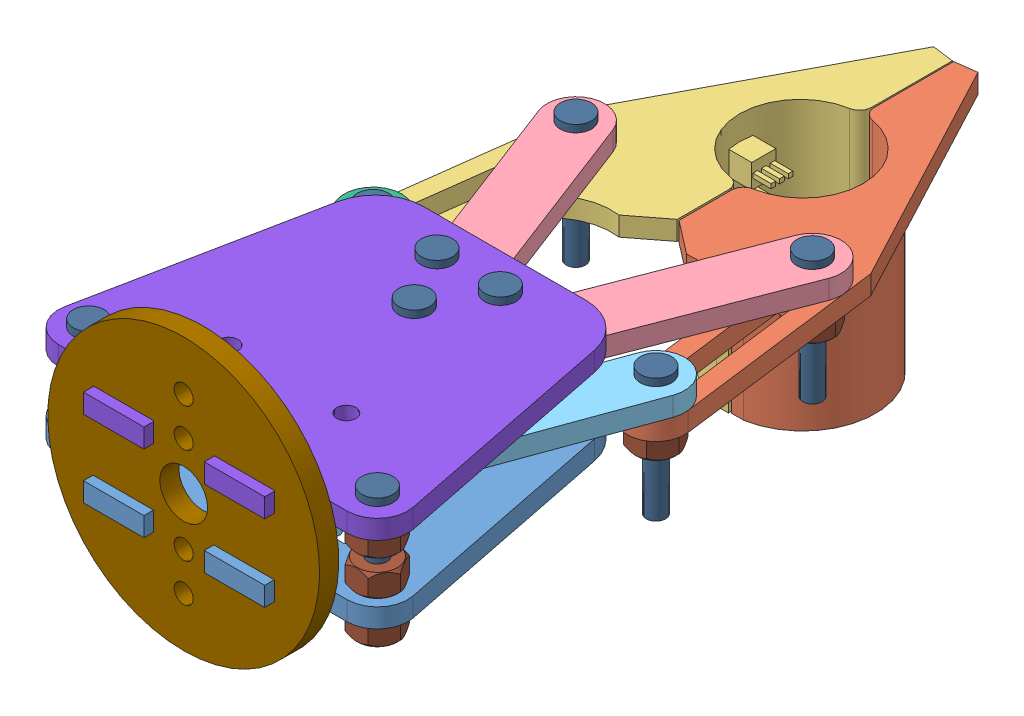
SolidWorks assembly Analyzing Arm, configuration Default. Lengths in mm.
Overall size (71.8 56.15 131.35).
40 component instances, 11 part files, 49 mates.
Components (placement in the parent):
- Gripper2-1: Gripper2 [Predeterminado] at origin size (71.8 56.15 131.35) (flexible)
  - Base grip-1: Base grip [Predeterminado] at (-28.7905 -8.0804 25) size (57.8 3.17 54.76)
  - Gripp2-3: Gripp2 [Predeterminado] at (12.4805 -1.7304 -60.3117) x (-0.991775 0 0.127995) z (0.127995 0 0.991775) size (24.38 32 79.76)
  - Gripp-3: Gripp [Predeterminado] at (-10.0632 -4.9054 -60.311) x (0.991774 0 0.127998) z (-0.127998 0 0.991774) size (24.38 32 79.76)
  - eslabon dos-1: eslabon dos [Predeterminado] at (9.1807 -1.7304 -39.3783) x (0.358372 0 -0.933579) z (0.933579 0 0.358372) size (49.52 3.17 9.53)
  - eslabon dos-2: eslabon dos [Predeterminado] at (-6.7627 -1.7304 -39.3782) x (0.358414 0 0.933563) z (-0.933563 0 0.358414) size (49.52 3.17 9.53)
  - eslabon engrane servo-1: eslabon engrane servo [Predeterminado] at (22.2724 -1.7304 -6.1668) x (-0.341868 0 0.939748) z (-0.939748 0 -0.341868) size (56.02 3.17 23.48)
  - eslabon engrane servo - copia-1: eslabon engrane servo - copia [Predeterminado] at (-10.9033 -1.7304 -9.423) x (0.341912 0 0.939732) z (-0.939732 0 0.341912) size (56.51 3.17 22.67)
  - separadores-1: separadores [Predeterminado] at (-8.5405 -4.9054 11) x (0.999665 0 -0.025874) z (0.025874 0 0.999665) size (6.35 3.17 6.35)
  - separadores-2: separadores [Predeterminado] at (-8.5405 1.4446 11) x (0.999761 0 0.021872) z (-0.021872 0 0.999761) size (6.35 3.17 6.35)
  - separadores-4: separadores [Predeterminado] at (-4.0405 -4.9054 -19) x (0.999761 0 0.021872) z (-0.021872 0 0.999761) size (6.35 3.17 6.35)
  - separadores-5: separadores [Predeterminado] at (6.4595 1.4446 -19) x (0.999761 0 0.021872) z (-0.021872 0 0.999761) size (6.35 3.17 6.35)
  - separadores-6: separadores [Predeterminado] at (-4.0405 1.4446 -19) x (0.999761 0 0.021872) z (-0.021872 0 0.999761) size (6.35 3.17 6.35)
  - separadores-7: separadores [Predeterminado] at (6.4595 -4.9054 -19) x (0.999761 0 0.021872) z (-0.021872 0 0.999761) size (6.35 3.17 6.35)
  - bse grip superior-2: bse grip superior [Predeterminado] at (-28.7905 4.6196 25) size (57.8 3.17 54.76)
  - base gripper servo-1: base gripper servo [Predeterminado] at (1.2095 -0.0804 28.175) x (1 0 0) z (0 1 0) size (45 3.17 45)
- Mosmar-1: Mosmar [Default] at (25.1104 8.9946 20) x (0.920505 0 -0.390731) z (0 -1 0) size (5.17 5.17 21.2)
- Mosmar-2: Mosmar [Default] at (-22.217 2.6446 -26.5893) x (1 0 0) z (0 -1 0) size (5.17 5.17 21.2)
- Mosmar-3: Mosmar [Default] at (24.6342 2.6446 -26.5899) x (1 0 0) z (0 -1 0) size (5.17 5.17 21.2)
- Mosmar-4: Mosmar [Default] at (-18.3771 2.6446 -56.3425) x (1 0 0) z (0 -1 0) size (5.17 5.17 21.2)
- Mosmar-5: Mosmar [Default] at (-22.6915 8.9946 20) x (1 0 0) z (0 -1 0) size (5.17 5.17 21.2)
- Mosmar-6: Mosmar [Default] at (20.7943 2.6446 -56.3432) x (1 0 0) z (0 -1 0) size (5.17 5.17 21.2)
- Mosmar-7: Mosmar [Default] at (6.4595 8.9946 -19) x (1 0 0) z (0 -1 0) size (5.17 5.17 21.2)
- Mosmar-8: Mosmar [Default] at (1.2095 8.9946 -10) x (1 0 0) z (0 -1 0) size (5.17 5.17 21.2)
- Mosmar-9: Mosmar [Default] at (-4.0405 8.9946 -19) x (1 0 0) z (0 -1 0) size (5.17 5.17 21.2)
- Nut-1: Nut [Default] at (25.1104 0.8696 20) x (1 0 0) z (0 1 0) size (8.54 7.6 3.75)
- Nut-2: Nut [Default] at (25.1104 -11.8304 20) x (1 0 0) z (0 1 0) size (8.54 7.6 3.75)
- Nut-3: Nut [Default] at (24.6342 -8.6554 -26.5899) x (1 0 0) z (0 1 0) size (8.54 7.6 3.75)
- Nut-4: Nut [Default] at (-18.3771 -8.6554 -56.3425) x (1 0 0) z (0 1 0) size (8.54 7.6 3.75)
- Nut-5: Nut [Default] at (25.1104 -4.9054 20) x (1 0 0) z (0 1 0) size (8.54 7.6 3.75)
- Nut-6: Nut [Default] at (-22.6915 0.8696 20) x (1 0 0) z (0 1 0) size (8.54 7.6 3.75)
- Nut-7: Nut [Default] at (-22.6915 -11.8304 20) x (1 0 0) z (0 1 0) size (8.54 7.6 3.75)
- Nut-8: Nut [Default] at (-22.6915 -4.9054 20) x (1 0 0) z (0 1 0) size (8.54 7.6 3.75)
- Nut-9: Nut [Default] at (-22.217 -8.6554 -26.5893) x (1 0 0) z (0 1 0) size (8.54 7.6 3.75)
- Nut-10: Nut [Default] at (20.7943 -8.6554 -56.3432) x (1 0 0) z (0 1 0) size (8.54 7.6 3.75)
- Nut-11: Nut [Default] at (1.2095 0.8696 -10) x (1 0 0) z (0 1 0) size (8.54 7.6 3.75)
- Nut-12: Nut [Default] at (1.2095 -4.9054 -10) x (1 0 0) z (0 1 0) size (8.54 7.6 3.75)
- Nut-13: Nut [Default] at (1.2095 -11.8304 -10) x (1 0 0) z (0 1 0) size (8.54 7.6 3.75)
- Nut-14: Nut [Default] at (6.4595 -11.8304 -19) x (1 0 0) z (0 1 0) size (8.54 7.6 3.75)
- Nut-15: Nut [Default] at (-4.0405 -11.8304 -19) x (1 0 0) z (0 1 0) size (8.54 7.6 3.75)
Mates (geometry in assembly coordinates):
- Concentric1: concentric anti-aligned: cylinder of Gripper2-1/eslabon dos-1 through (20.7943 1.4446 -56.3432) axis (0 -1 0) radius 1.5875; cylinder of Mosmar-6 through (20.7943 -18.5554 -56.3432) axis (0 1 0) radius 1.59
- Coincident1: coincident anti-aligned: plane of Gripper2-1/eslabon dos-1 through (6.4595 1.4446 -19) normal (0 1 0); plane of Mosmar-6 through (20.7943 1.4446 -56.3432) normal (0 -1 0)
- Concentric2: concentric anti-aligned: cylinder of Gripper2-1/eslabon engrane servo-1 through (24.6342 1.4446 -26.5899) axis (0 -1 0) radius 1.5875; cylinder of Mosmar-3 through (24.6342 -18.5554 -26.5899) axis (0 1 0) radius 1.59
- Coincident2: coincident anti-aligned: plane of Gripper2-1/eslabon engrane servo-1 through (24.6342 1.4446 -26.5899) normal (0 1 0); circle of Mosmar-3
- Concentric3: concentric anti-aligned: cylinder of Gripper2-1/eslabon dos-2 through (-18.3771 1.4446 -56.3425) axis (0 -1 0) radius 1.5875; cylinder of Mosmar-4 through (-18.3771 -18.5554 -56.3425) axis (0 1 0) radius 1.59
- Coincident3: coincident anti-aligned: plane of Gripper2-1/eslabon dos-2 through (-18.3771 1.4446 -56.3425) normal (0 1 0); plane of Mosmar-4 through (-18.3771 1.4446 -56.3425) normal (0 -1 0)
- Concentric4: concentric anti-aligned: cylinder of Gripper2-1/eslabon engrane servo - copia-1 through (-22.217 1.4446 -26.5893) axis (0 -1 0) radius 1.5875; cylinder of Mosmar-2 through (-22.217 -18.5554 -26.5893) axis (0 1 0) radius 1.59
- Coincident4: coincident anti-aligned: plane of Gripper2-1/eslabon engrane servo - copia-1 through (-22.217 1.4446 -26.5893) normal (0 1 0); plane of Mosmar-2 through (-22.217 1.4446 -26.5893) normal (0 -1 0)
- Concentric7: concentric aligned: cylinder of Gripper2-1/bse grip superior-2 through (25.1104 4.6196 20) axis (0 1 0) radius 1.5875; cylinder of Mosmar-1 through (25.1104 -12.2054 20) axis (0 1 0) radius 1.59
- Coincident5: coincident anti-aligned: plane of Gripper2-1/bse grip superior-2 through (14.651 7.7946 -17) normal (0 1 0); plane of Mosmar-1 through (25.1104 7.7946 20) normal (0 -1 0)
- Concentric10: concentric aligned: circle of Gripper2-1/bse grip superior-2; cylinder of Mosmar-5 through (-22.6915 -12.2054 20) axis (0 1 0) radius 1.59
- Coincident6: coincident anti-aligned: plane of Gripper2-1/bse grip superior-2 through (14.651 7.7946 -17) normal (0 1 0); plane of Mosmar-5 through (-22.6915 7.7946 20) normal (0 -1 0)
- Concentric12: concentric aligned: circle of Gripper2-1/bse grip superior-2; cylinder of Mosmar-7 through (6.4595 -12.2054 -19) axis (0 1 0) radius 1.59
- Coincident7: coincident anti-aligned: plane of Gripper2-1/bse grip superior-2 through (14.651 7.7946 -17) normal (0 1 0); plane of Mosmar-7 through (6.4595 7.7946 -19) normal (0 -1 0)
- Concentric13: concentric aligned: cylinder of Gripper2-1/bse grip superior-2 through (1.2095 4.6196 -10) axis (0 1 0) radius 1.5875; cylinder of Mosmar-8 through (1.2095 -12.2054 -10) axis (0 1 0) radius 1.59
- Coincident8: coincident anti-aligned: plane of Gripper2-1/bse grip superior-2 through (14.651 7.7946 -17) normal (0 1 0); plane of Mosmar-8 through (1.2095 7.7946 -10) normal (0 -1 0)
- Concentric14: concentric anti-aligned: cylinder of Gripper2-1/bse grip superior-2 through (-4.0405 7.7946 -19) axis (0 -1 0) radius 1.5875; cylinder of Mosmar-9 through (-4.0405 -12.2054 -19) axis (0 1 0) radius 1.59
- Coincident9: coincident anti-aligned: plane of Gripper2-1/bse grip superior-2 through (14.651 7.7946 -17) normal (0 1 0); plane of Mosmar-7 through (6.4595 7.7946 -19) normal (0 -1 0)
- Coincident10: coincident anti-aligned: plane of Gripper2-1/bse grip superior-2 through (14.651 7.7946 -17) normal (0 1 0); plane of Mosmar-9 through (-4.0405 7.7946 -19) normal (0 -1 0)
- Concentric15: concentric anti-aligned: cylinder of Mosmar-1 through (25.1104 -12.2054 20) axis (0 1 0) radius 1.59; cylinder of Nut-1 through (25.1104 4.6196 20) axis (0 -1 0) radius 1.59
- Coincident11: coincident anti-aligned: plane of Gripper2-1/bse grip superior-2 through (14.651 4.6196 -17) normal (0 -1 0); plane of Nut-1 through (25.1104 4.6196 20) normal (0 1 0)
- Concentric16: concentric anti-aligned: cylinder of Mosmar-1 through (25.1104 -12.2054 20) axis (0 1 0) radius 1.59; cylinder of Nut-5 through (25.1104 -1.1554 20) axis (0 -1 0) radius 1.59
- Coincident12: coincident anti-aligned: plane of Gripper2-1/Base grip-1 through (14.651 -4.9054 -17) normal (0 1 0); plane of Nut-5 through (25.1104 -4.9054 20) normal (0 -1 0)
- Concentric17: concentric anti-aligned: cylinder of Mosmar-1 through (25.1104 -12.2054 20) axis (0 1 0) radius 1.59; cylinder of Nut-2 through (25.1104 -8.0804 20) axis (0 -1 0) radius 1.59
- Coincident13: coincident anti-aligned: plane of Gripper2-1/Base grip-1 through (14.651 -8.0804 -17) normal (0 -1 0); plane of Nut-2 through (25.1104 -8.0804 20) normal (0 1 0)
- Concentric18: concentric anti-aligned: cylinder of Mosmar-5 through (-22.6915 -12.2054 20) axis (0 1 0) radius 1.59; cylinder of Nut-6 through (-22.6915 4.6196 20) axis (0 -1 0) radius 1.59
- Concentric19: concentric anti-aligned: cylinder of Mosmar-5 through (-22.6915 -12.2054 20) axis (0 1 0) radius 1.59; cylinder of Nut-8 through (-22.6915 -1.1554 20) axis (0 -1 0) radius 1.59
- Concentric20: concentric anti-aligned: cylinder of Mosmar-5 through (-22.6915 -12.2054 20) axis (0 1 0) radius 1.59; cylinder of Nut-7 through (-22.6915 -8.0804 20) axis (0 -1 0) radius 1.59
- Coincident14: coincident anti-aligned: plane of Gripper2-1/Base grip-1 through (14.651 -8.0804 -17) normal (0 -1 0); plane of Nut-7 through (-22.6915 -8.0804 20) normal (0 1 0)
- Coincident15: coincident anti-aligned: plane of Gripper2-1/bse grip superior-2 through (14.651 4.6196 -17) normal (0 -1 0); plane of Nut-6 through (-22.6915 4.6196 20) normal (0 1 0)
- Coincident16: coincident anti-aligned: plane of Gripper2-1/Base grip-1 through (14.651 -4.9054 -17) normal (0 1 0); plane of Nut-8 through (-22.6915 -4.9054 20) normal (0 -1 0)
- Concentric21: concentric anti-aligned: cylinder of Mosmar-3 through (24.6342 -18.5554 -26.5899) axis (0 1 0) radius 1.59; cylinder of Nut-3 through (24.6342 -4.9054 -26.5899) axis (0 -1 0) radius 1.59
- Concentric22: concentric anti-aligned: cylinder of Mosmar-6 through (20.7943 -18.5554 -56.3432) axis (0 1 0) radius 1.59; cylinder of Nut-10 through (20.7943 -4.9054 -56.3432) axis (0 -1 0) radius 1.59
- Concentric23: concentric anti-aligned: cylinder of Mosmar-2 through (-22.217 -18.5554 -26.5893) axis (0 1 0) radius 1.59; cylinder of Nut-9 through (-22.217 -4.9054 -26.5893) axis (0 -1 0) radius 1.59
- Concentric25: concentric anti-aligned: cylinder of Mosmar-4 through (-18.3771 -18.5554 -56.3425) axis (0 1 0) radius 1.59; cylinder of Nut-4 through (-18.3771 -4.9054 -56.3425) axis (0 -1 0) radius 1.59
- Coincident17: coincident anti-aligned: plane of Gripper2-1/Gripp2-3 through (8.0732 -4.9054 -39.577) normal (0 -1 0); plane of Nut-3 through (24.6342 -4.9054 -26.5899) normal (0 1 0)
- Coincident18: coincident anti-aligned: plane of Gripper2-1/Gripp2-3 through (8.0732 -4.9054 -39.577) normal (0 -1 0); circle of Nut-10
- Coincident19: coincident anti-aligned: plane of Gripper2-1/Gripp-3 through (-5.656 -4.9054 -39.5763) normal (0 -1 0); plane of Nut-9 through (-22.217 -4.9054 -26.5893) normal (0 1 0)
- Coincident20: coincident anti-aligned: plane of Gripper2-1/Gripp-3 through (-5.656 -4.9054 -39.5763) normal (0 -1 0); plane of Nut-4 through (-18.3771 -4.9054 -56.3425) normal (0 1 0)
- Concentric26: concentric anti-aligned: cylinder of Mosmar-8 through (1.2095 -12.2054 -10) axis (0 1 0) radius 1.59; cylinder of Nut-11 through (1.2095 4.6196 -10) axis (0 -1 0) radius 1.59
- Coincident21: coincident anti-aligned: plane of Gripper2-1/bse grip superior-2 through (14.651 4.6196 -17) normal (0 -1 0); plane of Nut-11 through (1.2095 4.6196 -10) normal (0 1 0)
- Concentric27: concentric anti-aligned: cylinder of Mosmar-8 through (1.2095 -12.2054 -10) axis (0 1 0) radius 1.59; cylinder of Nut-12 through (1.2095 -1.1554 -10) axis (0 -1 0) radius 1.59
- Coincident22: coincident anti-aligned: plane of Gripper2-1/Base grip-1 through (14.651 -4.9054 -17) normal (0 1 0); plane of Nut-12 through (1.2095 -4.9054 -10) normal (0 -1 0)
- Concentric28: concentric anti-aligned: cylinder of Mosmar-8 through (1.2095 -12.2054 -10) axis (0 1 0) radius 1.59; cylinder of Nut-13 through (1.2095 -8.0804 -10) axis (0 -1 0) radius 1.59
- Coincident23: coincident anti-aligned: plane of Gripper2-1/Base grip-1 through (14.651 -8.0804 -17) normal (0 -1 0); circle of Nut-13
- Concentric29: concentric anti-aligned: cylinder of Mosmar-7 through (6.4595 -12.2054 -19) axis (0 1 0) radius 1.59; cylinder of Nut-14 through (6.4595 -8.0804 -19) axis (0 -1 0) radius 1.59
- Coincident24: coincident anti-aligned: plane of Gripper2-1/Base grip-1 through (14.651 -8.0804 -17) normal (0 -1 0); circle of Nut-14
- Concentric30: concentric anti-aligned: cylinder of Mosmar-9 through (-4.0405 -12.2054 -19) axis (0 1 0) radius 1.59; cylinder of Nut-15 through (-4.0405 -8.0804 -19) axis (0 -1 0) radius 1.59
- Coincident26: coincident anti-aligned: plane of Gripper2-1/Base grip-1 through (14.651 -8.0804 -17) normal (0 -1 0); plane of Nut-15 through (-4.0405 -8.0804 -19) normal (0 1 0)
